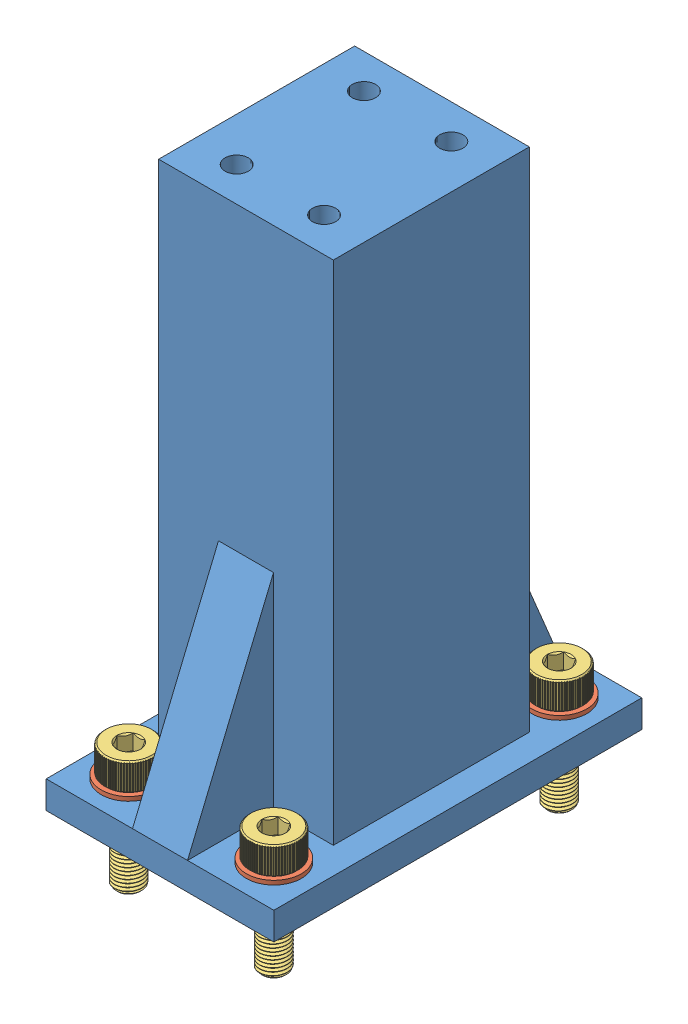
SolidWorks assembly SUB_3 Nozzle Base Assmebly, configuration Default. Lengths in mm.
Overall size (33.1 87.16 53.5).
13 component instances, 4 part files, 32 mates.
Components (placement in the parent):
- M22b_3 Nozzle Holder-1: M22b_3 Nozzle Holder [Default] at (18.5656 24.843 36.6275) size (33.1 77.7 53.5)
- M38_98689A113_General Purpose 18-8 Stainless Steel Washer-1: M38_98689A113_General Purpose 18-8 Stainless Steel Washer [98689A113] at (8.0156 25.443 57.3775) x (0.983948 0 -0.178454) z (0 -1 0) size (8 8 0.6)
- M38_98689A113_General Purpose 18-8 Stainless Steel Washer-2: M38_98689A113_General Purpose 18-8 Stainless Steel Washer [98689A113] at (8.0156 25.443 15.8775) x (0.922179 0 -0.386764) z (0 -1 0) size (8 8 0.6)
- M38_98689A113_General Purpose 18-8 Stainless Steel Washer-3: M38_98689A113_General Purpose 18-8 Stainless Steel Washer [98689A113] at (29.1156 25.443 15.8775) x (0.990958 0 -0.134172) z (0 -1 0) size (8 8 0.6)
- M38_98689A113_General Purpose 18-8 Stainless Steel Washer-4: M38_98689A113_General Purpose 18-8 Stainless Steel Washer [98689A113] at (29.1156 25.443 57.3775) x (0.996255 0 0.086463) z (0 -1 0) size (8 8 0.6)
- M37_90751A118_18-8 Stainless Steel Socket Head Screws-1: M37_90751A118_18-8 Stainless Steel Socket Head Screws [90751A118] at (8.0156 25.443 57.3775) x (0.866025 0 0.5) z (0 -1 0) size (7 7 18.23)
- M37_90751A118_18-8 Stainless Steel Socket Head Screws-2: M37_90751A118_18-8 Stainless Steel Socket Head Screws [90751A118] at (8.0156 25.443 15.8775) x (0.866025 0 -0.5) z (0 -1 0) size (7 7 18.23)
- M37_90751A118_18-8 Stainless Steel Socket Head Screws-3: M37_90751A118_18-8 Stainless Steel Socket Head Screws [90751A118] at (29.1156 25.443 15.8775) x (0.866025 0 -0.5) z (0 -1 0) size (7 7 18.23)
- M37_90751A118_18-8 Stainless Steel Socket Head Screws-4: M37_90751A118_18-8 Stainless Steel Socket Head Screws [90751A118] at (29.1156 25.443 57.3775) x (0.866025 0 -0.5) z (0 -1 0) size (7 7 18.23)
- M42_91828A211_18-8 Stainless Steel Hex Nut-5: M42_91828A211_18-8 Stainless Steel Hex Nut [91828A211] at (12.2156 92.343 45.8775) x (0.866025 0 -0.5) z (0 -1 0) size (5.5 6.35 2.78)
- M42_91828A211_18-8 Stainless Steel Hex Nut-6: M42_91828A211_18-8 Stainless Steel Hex Nut [91828A211] at (24.9156 92.343 45.8775) x (0.866025 0 -0.5) z (0 -1 0) size (5.5 6.35 2.78)
- M42_91828A211_18-8 Stainless Steel Hex Nut-7: M42_91828A211_18-8 Stainless Steel Hex Nut [91828A211] at (24.9156 92.343 27.3775) x (0.866025 0 -0.5) z (0 -1 0) size (5.5 6.35 2.78)
- M42_91828A211_18-8 Stainless Steel Hex Nut-8: M42_91828A211_18-8 Stainless Steel Hex Nut [91828A211] at (12.2156 92.343 27.3775) x (0.866025 0 -0.5) z (0 -1 0) size (5.5 6.35 2.78)
Mates (geometry in assembly coordinates):
- Concentric1: concentric aligned: cylinder of New 3 Nozzle Holder - Copy-1 through (8.0156 20.843 57.3775) axis (0 1 0) radius 2.25; cylinder of 98689A113_General Purpose 18-8 Stainless Steel Washer-1 through (8.0156 24.843 57.3775) axis (0 1 0) radius 2.15
- Coincident1: coincident anti-aligned: plane of New 3 Nozzle Holder - Copy-1 through (18.5656 24.843 36.6275) normal (0 1 0); plane of 98689A113_General Purpose 18-8 Stainless Steel Washer-1 through (8.0156 24.843 57.3775) normal (0 -1 0)
- Concentric2: concentric aligned: cylinder of New 3 Nozzle Holder - Copy-1 through (29.1156 20.843 57.3775) axis (0 1 0) radius 2.25; cylinder of 98689A113_General Purpose 18-8 Stainless Steel Washer-4 through (29.1156 24.843 57.3775) axis (0 1 0) radius 2.15
- Coincident2: coincident anti-aligned: plane of New 3 Nozzle Holder - Copy-1 through (18.5656 24.843 36.6275) normal (0 1 0); plane of 98689A113_General Purpose 18-8 Stainless Steel Washer-4 through (29.1156 24.843 57.3775) normal (0 -1 0)
- Concentric3: concentric aligned: cylinder of New 3 Nozzle Holder - Copy-1 through (29.1156 20.843 15.8775) axis (0 1 0) radius 2.25; cylinder of 98689A113_General Purpose 18-8 Stainless Steel Washer-3 through (29.1156 24.843 15.8775) axis (0 1 0) radius 2.15
- Coincident3: coincident anti-aligned: plane of New 3 Nozzle Holder - Copy-1 through (18.5656 24.843 36.6275) normal (0 1 0); plane of 98689A113_General Purpose 18-8 Stainless Steel Washer-3 through (29.1156 24.843 15.8775) normal (0 -1 0)
- Concentric4: concentric aligned: cylinder of New 3 Nozzle Holder - Copy-1 through (8.0156 20.843 15.8775) axis (0 1 0) radius 2.25; cylinder of 98689A113_General Purpose 18-8 Stainless Steel Washer-2 through (8.0156 24.843 15.8775) axis (0 1 0) radius 2.15
- Coincident4: coincident anti-aligned: plane of New 3 Nozzle Holder - Copy-1 through (18.5656 24.843 36.6275) normal (0 1 0); plane of 98689A113_General Purpose 18-8 Stainless Steel Washer-2 through (8.0156 24.843 15.8775) normal (0 -1 0)
- Coincident5: coincident anti-aligned: plane of 98689A113_General Purpose 18-8 Stainless Steel Washer-1 through (8.0156 25.443 57.3775) normal (0 1 0); plane of 90751A118_18-8 Stainless Steel Socket Head Screws-1 through (6.3706 25.443 60.2268) normal (0 -1 0)
- Concentric5: concentric anti-aligned: circle of 98689A113_General Purpose 18-8 Stainless Steel Washer-1; circle of 90751A118_18-8 Stainless Steel Socket Head Screws-1
- Parallel1: parallel aligned: plane of New 3 Nozzle Holder - Copy-1 through (5.8656 136.719 50.8775) normal (0 0 1); plane of 90751A118_18-8 Stainless Steel Socket Head Screws-1 through (8.8816 27.193 55.8775) normal (0 0 1)
- Coincident7: coincident anti-aligned: plane of 98689A113_General Purpose 18-8 Stainless Steel Washer-4 through (29.1156 25.443 57.3775) normal (0 1 0); plane of 90751A118_18-8 Stainless Steel Socket Head Screws-4 through (30.7606 25.443 60.2268) normal (0 -1 0)
- Concentric6: concentric anti-aligned: circle of 98689A113_General Purpose 18-8 Stainless Steel Washer-4; circle of 90751A118_18-8 Stainless Steel Socket Head Screws-4
- Parallel2: parallel anti-aligned: plane of New 3 Nozzle Holder - Copy-1 through (5.8656 136.719 50.8775) normal (0 0 1); plane of 90751A118_18-8 Stainless Steel Socket Head Screws-4 through (28.2495 27.193 58.8775) normal (0 0 -1)
- Coincident9: coincident anti-aligned: plane of 98689A113_General Purpose 18-8 Stainless Steel Washer-3 through (29.1156 25.443 15.8775) normal (0 1 0); plane of 90751A118_18-8 Stainless Steel Socket Head Screws-3 through (30.7606 25.443 18.7268) normal (0 -1 0)
- Concentric7: concentric anti-aligned: circle of 98689A113_General Purpose 18-8 Stainless Steel Washer-3; circle of 90751A118_18-8 Stainless Steel Socket Head Screws-3
- Parallel3: parallel aligned: plane of New 3 Nozzle Holder - Copy-1 through (5.8656 136.719 22.3775) normal (0 0 -1); plane of 90751A118_18-8 Stainless Steel Socket Head Screws-3 through (28.2495 27.193 17.3775) normal (0 0 -1)
- Coincident11: coincident anti-aligned: plane of 98689A113_General Purpose 18-8 Stainless Steel Washer-2 through (8.0156 25.443 15.8775) normal (0 1 0); plane of 90751A118_18-8 Stainless Steel Socket Head Screws-2 through (9.6606 25.443 18.7268) normal (0 -1 0)
- Concentric8: concentric anti-aligned: circle of 98689A113_General Purpose 18-8 Stainless Steel Washer-2; circle of 90751A118_18-8 Stainless Steel Socket Head Screws-2
- Parallel4: parallel aligned: plane of New 3 Nozzle Holder - Copy-1 through (5.8656 136.719 22.3775) normal (0 0 -1); plane of 90751A118_18-8 Stainless Steel Socket Head Screws-2 through (7.1495 27.193 17.3775) normal (0 0 -1)
- Coincident12: coincident anti-aligned: plane of New 3 Nozzle Holder - Copy-1 through (18.5656 93.543 36.6275) normal (0 -1 0); plane of M42_91828A211_18-8 Stainless Steel Hex Nut-5 through (10.6278 93.543 48.6275) normal (0 1 0)
- Parallel5: parallel anti-aligned: plane of New 3 Nozzle Holder - Copy-1 through (13.9187 91.043 42.9275) normal (0 0 1); plane of M42_91828A211_18-8 Stainless Steel Hex Nut-5 through (10.6278 91.143 43.1275) normal (0 0 -1)
- Concentric9: concentric aligned: circle of New 3 Nozzle Holder - Copy-1; circle of M42_91828A211_18-8 Stainless Steel Hex Nut-5
- Concentric10: concentric: circle of New 3 Nozzle Holder - Copy-1; circle of M42_91828A211_18-8 Stainless Steel Hex Nut-8
- Concentric11: concentric anti-aligned: circle of New 3 Nozzle Holder - Copy-1; circle of M42_91828A211_18-8 Stainless Steel Hex Nut-7
- Concentric12: concentric anti-aligned: circle of New 3 Nozzle Holder - Copy-1; circle of M42_91828A211_18-8 Stainless Steel Hex Nut-6
- Coincident15: coincident anti-aligned: plane of New 3 Nozzle Holder - Copy-1 through (18.5656 93.543 36.6275) normal (0 -1 0); plane of M42_91828A211_18-8 Stainless Steel Hex Nut-6 through (23.3278 93.543 48.6275) normal (0 1 0)
- Coincident16: coincident: plane of New 3 Nozzle Holder - Copy-1 through (18.5656 93.543 36.6275) normal (0 -1 0); plane of M42_91828A211_18-8 Stainless Steel Hex Nut-8 through (10.6278 93.543 30.1275) normal (0 1 0)
- Coincident17: coincident anti-aligned: plane of New 3 Nozzle Holder - Copy-1 through (18.5656 93.543 36.6275) normal (0 -1 0); plane of M42_91828A211_18-8 Stainless Steel Hex Nut-7 through (23.3278 93.543 30.1275) normal (0 1 0)
- Parallel7: parallel anti-aligned: plane of New 3 Nozzle Holder - Copy-1 through (26.6187 91.043 42.9275) normal (0 0 1); plane of M42_91828A211_18-8 Stainless Steel Hex Nut-6 through (23.3278 91.143 43.1275) normal (0 0 -1)
- Parallel8: parallel anti-aligned: plane of New 3 Nozzle Holder - Copy-1 through (26.6187 91.043 24.4275) normal (0 0 1); plane of M42_91828A211_18-8 Stainless Steel Hex Nut-7 through (23.3278 91.143 24.6275) normal (0 0 -1)
- Parallel9: parallel anti-aligned: plane of New 3 Nozzle Holder - Copy-1 through (13.9187 91.043 24.4275) normal (0 0 1); plane of M42_91828A211_18-8 Stainless Steel Hex Nut-8 through (10.6278 91.143 24.6275) normal (0 0 -1)
